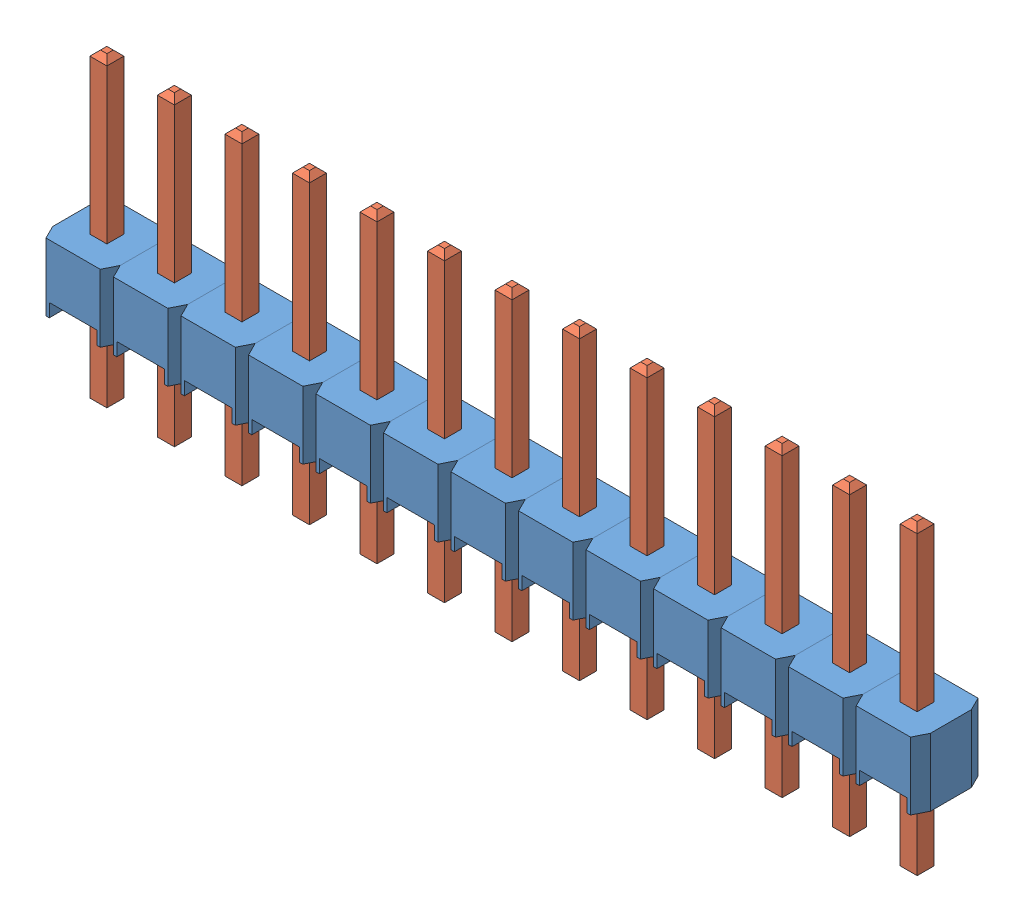
SolidWorks assembly Headers for Dagaya, configuration 3pin. Lengths in mm.
Overall size (33.02 11.54 2.54).
26 component instances, 2 part files, 3 mates.
Components (placement in the parent):
- PlasticHolder-1: PlasticHolder [Default] at (0.8273 2.9943 2.6053) x (1 0 0) z (0 0 -1)
- SinglePinStraight-1: SinglePinStraight [Default] at (0.8273 -2.5457 2.6053)
- SinglePinStraight-2: SinglePinStraight [Default] at (3.3673 -2.5457 2.6053)
- PlasticHolder-2: PlasticHolder [Default] at (3.3673 2.9943 2.6053) x (1 0 0) z (0 0 -1)
- PlasticHolder-3: PlasticHolder [Default] at (5.9073 2.9943 2.6053) x (1 0 0) z (0 0 -1)
- SinglePinStraight-3: SinglePinStraight [Default] at (5.9073 -2.5457 2.6053)
- PlasticHolder-4: PlasticHolder [Default] at (8.4473 2.9943 2.6053) x (1 0 0) z (0 0 -1)
- SinglePinStraight-4: SinglePinStraight [Default] at (8.4473 -2.5457 2.6053)
- PlasticHolder-5: PlasticHolder [Default] at (10.9873 2.9943 2.6053) x (1 0 0) z (0 0 -1)
- SinglePinStraight-5: SinglePinStraight [Default] at (10.9873 -2.5457 2.6053)
- PlasticHolder-6: PlasticHolder [Default] at (13.5273 2.9943 2.6053) x (1 0 0) z (0 0 -1)
- SinglePinStraight-6: SinglePinStraight [Default] at (13.5273 -2.5457 2.6053)
- SinglePinStraight-7: SinglePinStraight [Default] at (16.0673 -2.5457 2.6053)
- PlasticHolder-7: PlasticHolder [Default] at (16.0673 2.9943 2.6053) x (1 0 0) z (0 0 -1)
- PlasticHolder-8: PlasticHolder [Default] at (18.6073 2.9943 2.6053) x (1 0 0) z (0 0 -1)
- SinglePinStraight-8: SinglePinStraight [Default] at (18.6073 -2.5457 2.6053)
- PlasticHolder-9: PlasticHolder [Default] at (21.1473 2.9943 2.6053) x (1 0 0) z (0 0 -1)
- SinglePinStraight-9: SinglePinStraight [Default] at (21.1473 -2.5457 2.6053)
- PlasticHolder-10: PlasticHolder [Default] at (23.6873 2.9943 2.6053) x (1 0 0) z (0 0 -1)
- SinglePinStraight-10: SinglePinStraight [Default] at (23.6873 -2.5457 2.6053)
- PlasticHolder-11: PlasticHolder [Default] at (26.2273 2.9943 2.6053) x (1 0 0) z (0 0 -1)
- SinglePinStraight-11: SinglePinStraight [Default] at (26.2273 -2.5457 2.6053)
- PlasticHolder-12: PlasticHolder [Default] at (28.7673 2.9943 2.6053) x (1 0 0) z (0 0 -1)
- SinglePinStraight-12: SinglePinStraight [Default] at (28.7673 -2.5457 2.6053)
- PlasticHolder-13: PlasticHolder [Default] at (31.3073 2.9943 2.6053) x (1 0 0) z (0 0 -1)
- SinglePinStraight-13: SinglePinStraight [Default] at (31.3073 -2.5457 2.6053)
Mates (geometry in assembly coordinates):
- Distance1: distance = 6 mm: plane of SinglePinStraight-1 through (0.8273 8.9943 2.6053) normal (0 1 0); plane of PlasticHolder-1 through (0.8273 2.9943 2.6053) normal (0 1 0)
- Coincident2: coincident: line of PlasticHolder-1 through (0.5073 0.9543 2.2853) axis (0 1 0); line of SinglePinStraight-1 through (0.5073 8.7943 2.2853) axis (0 -1 0)
- Coincident4: coincident: line of PlasticHolder-1 through (1.1473 0.9543 2.2853) axis (0 1 0); line of SinglePinStraight-1 through (1.1473 8.7943 2.2853) axis (0 -1 0)
